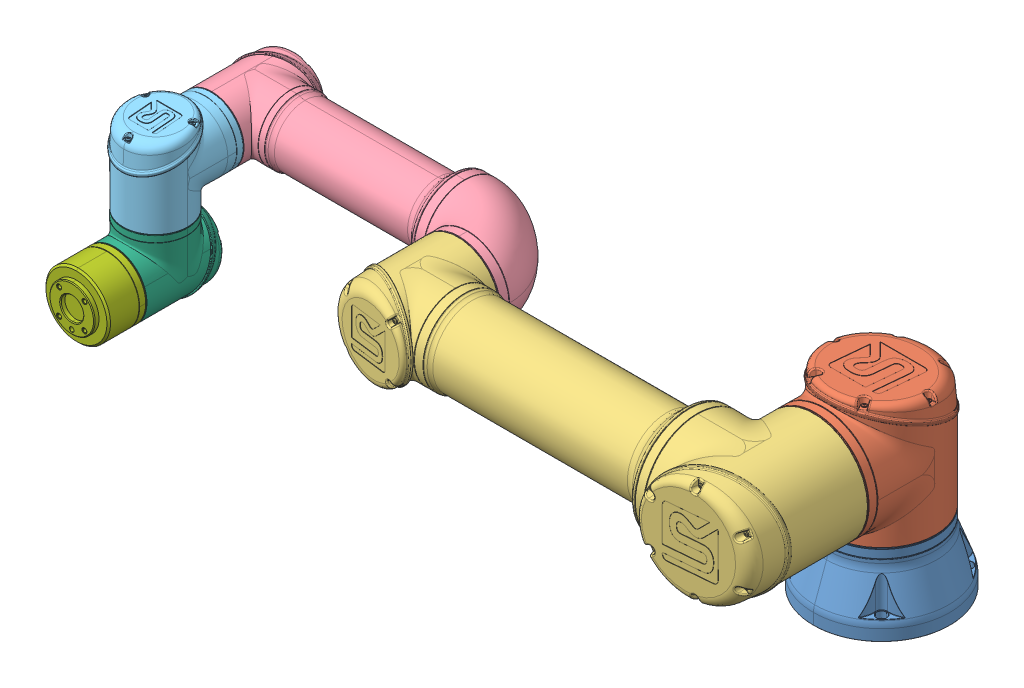
SolidWorks assembly eSeries_UR16e, configuration Default. Lengths in mm.
Overall size (992.78 279.84 385.7).
7 component instances, 7 part files, 18 mates.
Components (placement in the parent):
- base_no_cord-1: base_no_cord [Default] at origin size (190 99.5 190)
- Link_1-1: Link_1 [Default] at origin size (172.45 173.23 187.57)
- Link_2-1: Link_2 [Default] at (180.7 180.7 0) x (0 1 0) z (0 0 1) size (197.87 631.52 173.11)
- Link_3-1: Link_3 [Default] at (180.7 180.7 0) x (0 1 0) z (0 0 1) size (116.75 473.77 131.81)
- Link_4-1: Link_4 [Default] at (-838.4 1199.8 0) x (-1 0 0) z (0 0 1) size (105.37 114.49 221.67)
- Link_5-1: Link_5 [Default] at (-838.4 1199.8 0) x (-1 0 0) z (0 0 1) size (108.52 172.26 114.47)
- Link_6-1: Link_6 [Default] at (-838.4 1199.8 0) x (-1 0 0) z (0 0 1) size (90 95.8 59.65)
Mates (geometry in assembly coordinates):
- Coincident1: coincident anti-aligned: plane of base_no_cord-1 through (0 99.3 73.275) normal (0 1 0); plane of Link_1-1 through (0 99.3 -73.95) normal (0 -1 0)
- Concentric1: concentric anti-aligned: circle of base_no_cord-1; circle of Link_1-1
- Coincident2: coincident anti-aligned: plane of Link_1-1 through (0 253.975 94.6) normal (0 0 1); plane of Link_2-1 through (73.95 180.7 94.6) normal (0 0 -1)
- Concentric2: concentric anti-aligned: circle of Link_1-1; circle of Link_2-1
- Coincident4: coincident anti-aligned: plane of Link_2-1 through (-420.4 180.7 112.6) normal (0 0 -1); plane of Link_3-1 through (-420.4 180.7 112.6) normal (0 0 1)
- Concentric3: concentric aligned: circle of Link_2-1; circle of Link_3-1
- Coincident5: coincident anti-aligned: plane of Link_3-1 through (-838.4 180.7 95.7) normal (0 0 1); plane of Link_4-1 through (-838.4 180.7 95.7) normal (0 0 -1)
- Concentric4: concentric aligned: circle of Link_3-1; circle of Link_4-1
- Coincident7: coincident anti-aligned: plane of Link_4-1 through (-838.4 123.8 131.05) normal (0 -1 0); plane of Link_5-1 through (-838.4 123.8 174.15) normal (0 1 0)
- Concentric5: concentric aligned: circle of Link_4-1; circle of Link_5-1
- Coincident9: coincident anti-aligned: plane of Link_5-1 through (-821.8906 21.0373 231.05) normal (0 0 1); plane of Link_6-1 through (-821.2777 19.5594 231.05) normal (0 0 -1)
- Concentric6: concentric aligned: circle of Link_5-1; circle of Link_6-1
- Parallel1: parallel aligned: cylinder of base_no_cord-1 through (0 7.4 -93) axis (0 0 -1) radius 8.5; cylinder of Link_2-1 through (0 180.7 470.132) axis (0 0 -1) radius 75
- Perpendicular1: perpendicular: cylinder of Link_1-1 through (0 474.832 0) axis (0 -1 0) radius 75; cylinder of Link_2-1 through (-91.4 180.7 176) axis (-1 0 0) radius 55
- Parallel3: parallel aligned: cylinder of Link_2-1 through (-91.4 180.7 176) axis (-1 0 0) radius 55; cylinder of Link_3-1 through (-786.25 180.7 38.8) axis (-1 0 0) radius 42.5
- Parallel5: parallel anti-aligned: cylinder of Link_1-1 through (0 474.832 0) axis (0 -1 0) radius 75; cylinder of Link_4-1 through (-838.4 126.9 174.15) axis (0 1 0) radius 45
- Parallel6: parallel anti-aligned: cylinder of Link_3-1 through (-838.4 180.7 -9.7322) axis (0 0 1) radius 45; cylinder of Link_5-1 through (-838.4 60.85 227.95) axis (0 0 -1) radius 45
- Parallel7: parallel aligned: cylinder of Link_4-1 through (-838.4 126.9 174.15) axis (0 1 0) radius 45; cylinder of Link_6-1 through (-838.4 14.15 255.05) axis (0 1 0) radius 4.91
